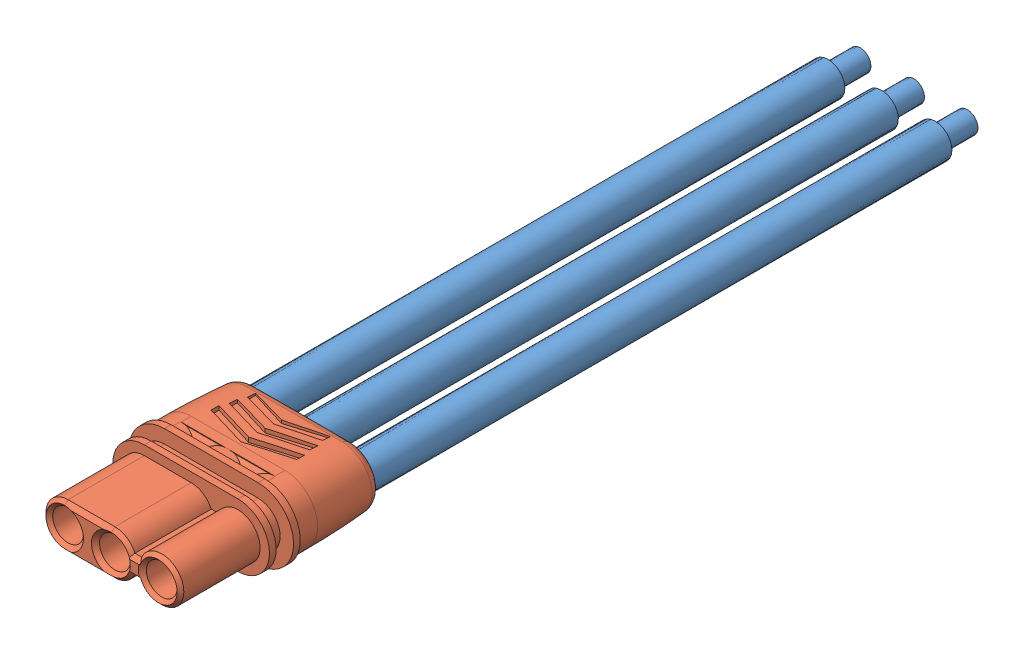
SolidWorks assembly 9, configuration 默认. Lengths in mm.
Overall size (12.3 9.21 60).
4 component instances, 2 part files, 0 mates.
Components (placement in the parent):
- 14-1: 14 [默认] at (4 0 -0.7) size (2.5 2.5 50)
- 14-2: 14 [默认] at (0 0 -0.7) x (0.422263 0.906473 0) z (0 0 1) size (2.5 2.5 50)
- 14-3: 14 [默认] at (-4 0 -0.7) size (2.5 2.5 50)
- 1-1: 1 [默认] at (-18.7519 0 2.7064) x (-1 0 0) z (0 0 1) size (12.3 9.21 15.16)
